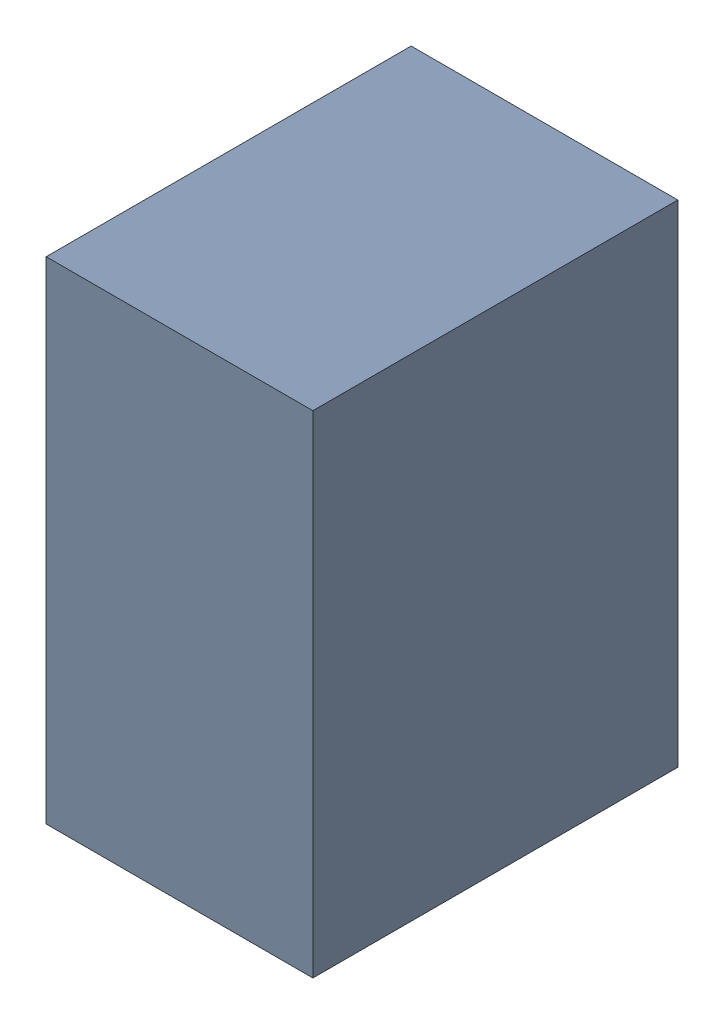
SolidWorks assembly C2_1, configuration Default. Lengths in mm.
Overall size (0.95 1.75 1.3).
2 component instances, 1 part files, 0 mates.
Components (placement in the parent):
- 5808185280-1: 5808185280 [Default] at (11.303 26.859 0) size (0.95 1.75 1.3)
  - Extruded_1_4-1: Extruded_1_4 [Default] at origin size (0.95 1.75 1.3)
